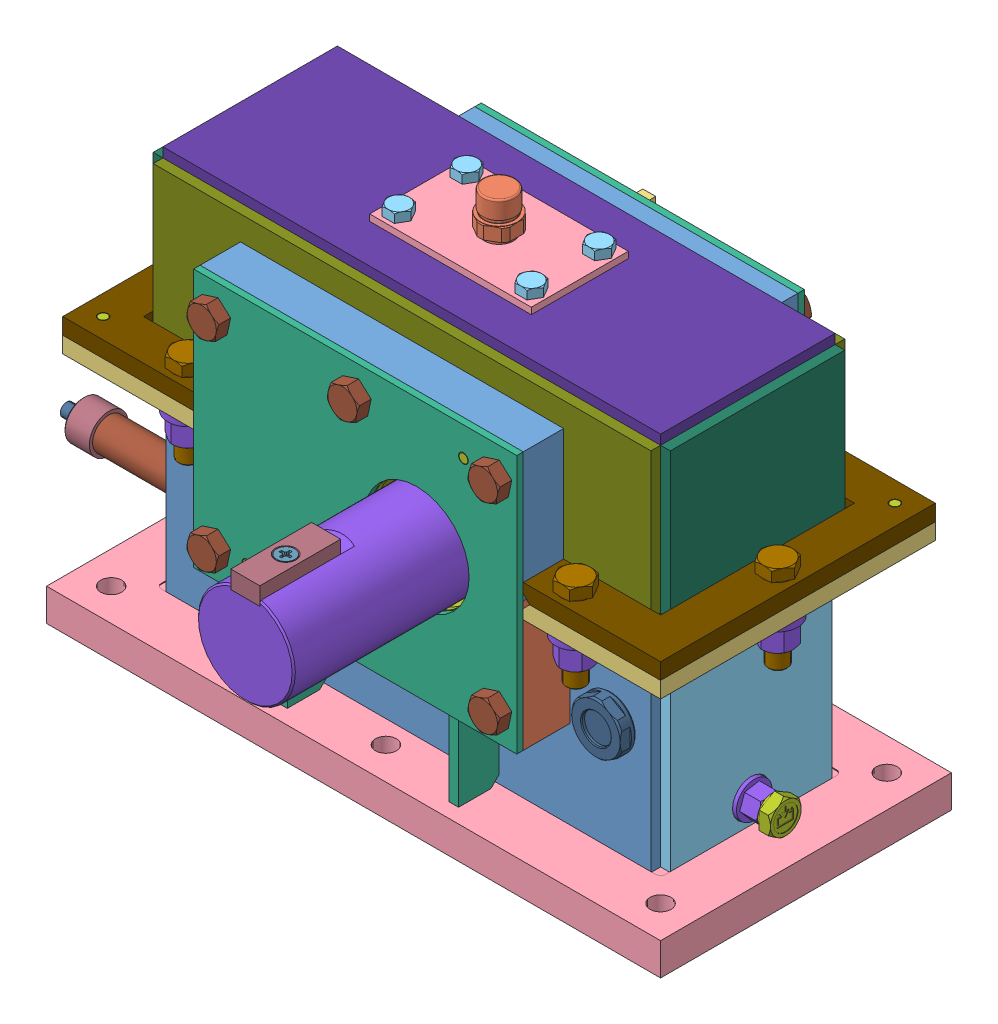
SolidWorks assembly reduktor, configuration Default. Lengths in mm.
Overall size (420 284 364.33).
123 component instances, 47 part files, 49 mates.
Components (placement in the parent):
- kuciste_bez_poklopca-1: kuciste_bez_poklopca [Default] at (-37.8332 -21.7055 -9.2797) size (410 284 180)
  - DONJE_KUCISTE-1: DONJE_KUCISTE [zajedno obrađeno] at (117.7992 130.0596 336.2434) size (410 154.5 180)
    - glavni_lim-1: glavni_lim [rupa za staklo] at (0 84.5 50) x (1 0 0) z (0 -1 0) size (300 6 130)
    - kockavratila-1: kockavratila [probusena_s_rupama_prednja] at (0 114.5 50) x (1 0 0) z (0 -1 0) size (200 35 80)
    - prirubnica_donja-1: prirubnica_donja [urezana_s_rupama] at (-100 144.5 0) size (85 10 170)
    - temeljna_ploca-1: temeljna_ploca [Default] at origin size (380 20 180)
    - bocni_lim-2: bocni_lim [cijevni registar] at (-150 84.5 0) x (0 0 -1) z (0 1 0) size (100 6 130)
    - glavni_lim-2: glavni_lim [Default] at (0 84.5 -56) x (1 0 0) z (0 -1 0) size (300 6 130)
    - kockavratila-2: kockavratila [probusena_s_rupama_zadnja] at (0 114.5 -50) x (-1 0 0) z (0 -1 0) size (200 35 80)
    - prirubnica_donja-2: prirubnica_donja [urezana_s_rupama] at (100 144.5 0) x (-1 0 0) z (0 0 -1) size (85 10 170)
    - bocni_lim-3: bocni_lim [irezan_ispust] at (156 84.5 0) x (0 0 1) z (0 -1 0) size (100 6 130)
    - rebro-1: rebro [Default] at (-50 47.25 68.5) x (0 -1 0) z (0 0 -1) size (54.5 6 25)
    - rebro-2: rebro [Default] at (50 47.25 68.5) x (0 1 0) z (0 0 -1) size (54.5 6 25)
    - rebro-3: rebro [Default] at (56 47.25 -68.5) x (0 1 0) z (0 0 1) size (54.5 6 25)
    - rebro-4: rebro [Default] at (-50 47.25 -68.5) x (0 1 0) z (0 0 1) size (54.5 6 25)
    - Oil fill plugs TCD.10x1.5-1: Oil fill plugs TCD.10x1.5 [Default] at (161.5 34.5 0) size (16 24.13 19)
    - Hexagon nut DIN 6331-M10-1: Hexagon nut DIN 6331-M10 [Default] at (154 34.5 0) x (0 -0.652064 0.758164) z (0 0.758164 0.652064) size (22 15 22)
    - Brass nut GH.M26x1.5-NK-1: Brass nut GH.M26x1.5-NK [Default] at (125 88.5 50) x (0 0 1) z (-0.706547 -0.707666 0) size (3.5 33 30)
    - Oil level sight glass GN 743-18-M26x1_5-A-1: Oil level sight glass GN 743-18-M26x1_5-A [Default] at (125 88.5 48) x (1 0 0) z (0 -1 0) size (32 17 32)
    - Prirubnica_c.reg._sklop-1: Prirubnica_c.reg._sklop [Default] at (-142.8722 78.3632 -24.5463) x (0 0.999301 0.037387) z (0 -0.037387 0.999301) size (33.22 66 33.22)
      - prirubnica_cijevnog_registra-1: prirubnica_cijevnog_registra [Default] at (-7.5365 11.1278 62.3717) size (20 50 20)
      - Gasket DIN 7603-AL-8-11_5-A(semering registra)-1: Gasket DIN 7603-AL-8-11_5-A(semering registra) [Default] at (-7.5365 26.6278 62.3717) x (0 -1 0) z (0.887885 0 0.460066) size (1 11.4 11.4)
      - Gasket DIN 7603-AL-8-11_5-A(semering registra)-2: Gasket DIN 7603-AL-8-11_5-A(semering registra) [Default] at (-7.5365 28.6278 62.3717) x (0 -1 0) z (-0.546944 0 0.837169) size (1 11.4 11.4)
      - Gasket DIN 7603-AL-8-11_5-A(semering registra)-3: Gasket DIN 7603-AL-8-11_5-A(semering registra) [Default] at (-7.5365 29.6278 62.3717) x (0 1 0) z (-0.564882 0 -0.825172) size (1 11.4 11.4)
      - Gasket DIN 7603-AL-8-11_5-A(semering registra)-4: Gasket DIN 7603-AL-8-11_5-A(semering registra) [Default] at (-7.5365 30.6278 62.3717) x (0 1 0) z (-0.564882 0 -0.825172) size (1 11.4 11.4)
      - Gasket DIN 7603-AL-8-11_5-A(semering registra)-5: Gasket DIN 7603-AL-8-11_5-A(semering registra) [Default] at (-7.5365 27.6278 62.3717) x (0 -1 0) z (-0.546944 0 0.837169) size (1 11.4 11.4)
      - M16x30-1: M16x30 [Default] at (-7.5365 77.1278 62.3717) x (0 -1 0) z (-0.546944 0 0.837169) size (46 24 24)
    - Prirubnica_c.reg._sklop-2: Prirubnica_c.reg._sklop [Default] at (-142.8722 84.718 -98.196) x (0 0.990097 0.140386) z (0 -0.140386 0.990097) size (33.22 66 33.22)
      - prirubnica_cijevnog_registra-1: prirubnica_cijevnog_registra [Default] at (-7.5365 11.1278 62.3717) size (20 50 20)
      - Gasket DIN 7603-AL-8-11_5-A(semering registra)-1: Gasket DIN 7603-AL-8-11_5-A(semering registra) [Default] at (-7.5365 26.6278 62.3717) x (0 -1 0) z (0.887885 0 0.460066) size (1 11.4 11.4)
      - Gasket DIN 7603-AL-8-11_5-A(semering registra)-2: Gasket DIN 7603-AL-8-11_5-A(semering registra) [Default] at (-7.5365 28.6278 62.3717) x (0 -1 0) z (-0.546944 0 0.837169) size (1 11.4 11.4)
      - Gasket DIN 7603-AL-8-11_5-A(semering registra)-3: Gasket DIN 7603-AL-8-11_5-A(semering registra) [Default] at (-7.5365 29.6278 62.3717) x (0 1 0) z (-0.564882 0 -0.825172) size (1 11.4 11.4)
      - Gasket DIN 7603-AL-8-11_5-A(semering registra)-4: Gasket DIN 7603-AL-8-11_5-A(semering registra) [Default] at (-7.5365 30.6278 62.3717) x (0 1 0) z (-0.564882 0 -0.825172) size (1 11.4 11.4)
      - Gasket DIN 7603-AL-8-11_5-A(semering registra)-5: Gasket DIN 7603-AL-8-11_5-A(semering registra) [Default] at (-7.5365 27.6278 62.3717) x (0 -1 0) z (-0.546944 0 0.837169) size (1 11.4 11.4)
      - M16x30-1: M16x30 [Default] at (-7.5365 77.1278 62.3717) x (0 -1 0) z (-0.546944 0 0.837169) size (46 24 24)
    - unutarnji lim-1: unutarnji lim [Default] at (-1.7035 28.2254 0) x (0.99863 -0.052336 0) z (0 0 -1) size (296.96 17.98 100)
  - GORNJE KUČIŠTE-1: GORNJE KUČIŠTE [zajednicki obrađena] at (84.6226 294.5596 336.2434) x (-1 0 0) z (0 0 1) size (370 129.5 170)
    - gornji bočni lim veći-1: gornji bočni lim veći [Default] at (-187.1766 -40 0) x (0 1 0) z (0 0 1) size (90 6 108)
    - gornji glavni lim-1: gornji glavni lim [Default] at (27.434 -40 -60) x (-1 0 0) z (0 1 0) size (308 6 90)
    - gornji_gornji lim ravni-1: gornji_gornji lim ravni [Default] at (-33.1766 -91 0) size (308 6 108)
    - prirubnica_gornja-1: prirubnica_gornja [prirubnica s rupama ] at origin size (85 10 170)
    - gornji bočni lim veći-2: gornji bočni lim veći [Default] at (126.8234 -40 0) x (0 1 0) z (0 0 1) size (90 6 108)
    - gornji glavni lim-2: gornji glavni lim [Default] at (-93.7872 -40 60) x (1 0 0) z (0 1 0) size (308 6 90)
    - prirubnica_gornja-2: prirubnica_gornja [prirubnica s rupama ] at (-66.3532 0 0) x (-1 0 0) z (0 0 -1) size (85 10 170)
    - gornja kocka vratila-1: gornja kocka vratila [prednja_probusena_s_rupama] at (-33.1766 -30 50) x (-1 0 0) z (0 1 0) size (200 35 80)
    - gornja kocka vratila-2: gornja kocka vratila [zadnja_probusena_s_rupama] at (-33.1766 -30 -50) x (1 0 0) z (0 1 0) size (200 35 80)
    - poklopac sa odzračnikom-1: poklopac sa odzračnikom [Default] at (-34.3484 -81.4985 -29.5408) x (-1 0 0) z (0 0 1) size (100 33 60)
      - Breather valve GN 881-M12x1_5-200-MS-M-1: Breather valve GN 881-M12x1_5-200-MS-M [Default] at (-1.1718 13.5015 29.5408) size (23 33 23.5)
      - Mounting nut GN 7430-M12x1_5-MS-1: Mounting nut GN 7430-M12x1_5-MS [Default] at (-1.1718 6.5015 29.5408) x (1 0 0) z (0 -1 0) size (16 17.5 3)
      - poklopac-1: poklopac [Default] at (-1.1718 9.5015 29.5408) size (100 4 60)
    - DIN933 M8x14mm-1: DIN933 M8x14mm [Default] at (-74.1766 -100.68 21) x (0 1 0) z (0 0 1) size (19.69 15.02 15.02)
    - DIN933 M8x14mm-2: DIN933 M8x14mm [Default] at (7.8234 -100.68 21) x (0 1 0) z (0 0 1) size (19.69 15.02 15.02)
    - DIN933 M8x14mm-3: DIN933 M8x14mm [Default] at (7.8234 -100.68 -21) x (0 1 0) z (0 0 1) size (19.69 15.02 15.02)
    - DIN933 M8x14mm-4: DIN933 M8x14mm [Default] at (-74.1766 -100.68 -21) x (0 1 0) z (0 0 1) size (19.69 15.02 15.02)
  - poklopac_vratila-1: poklopac_vratila [zajedno_obrađen_prednji] at (117.7992 284.5596 425.2434) x (1 0 0) z (0 1 0) size (200 17.13 160)
  - poklopac_vratila-2: poklopac_vratila [zajedno_obrađen] at (117.7992 284.5596 247.2434) x (1 0 0) z (0 -1 0) size (200 17.13 160)
  - parallel pin hardened_din-1: parallel pin hardened_din [DIN EN 28734 - 6 x 14 - A - St] at (290.2992 280.5596 263.7434) x (0 1 0) z (0 0 1) size (14 6 6)
  - parallel pin hardened_din-2: parallel pin hardened_din [DIN EN 28734 - 6 x 14 - A - St] at (184.7992 346.5596 411.2434) x (0 0 1) z (0 -1 0) size (14 6 6)
  - parallel pin hardened_din-3: parallel pin hardened_din [DIN EN 28734 - 6 x 14 - A - St] at (50.7992 222.5596 411.2434) x (0 0 1) z (-1 0 0) size (14 6 6)
  - parallel pin hardened_din-4: parallel pin hardened_din [DIN EN 28734 - 6 x 14 - A - St] at (50.7992 222.5596 247.2434) x (0 0 1) z (-1 0 0) size (14 6 6)
  - parallel pin hardened_din-5: parallel pin hardened_din [DIN EN 28734 - 6 x 14 - A - St] at (-54.7008 280.5596 408.7434) x (0 1 0) z (0 0 1) size (14 6 6)
  - parallel pin hardened_din-6: parallel pin hardened_din [DIN EN 28734 - 6 x 14 - A - St] at (184.7992 346.5596 247.2434) x (0 0 1) z (-1 0 0) size (14 6 6)
- podsklop_v2-1: podsklop_v2 [Default] at (87.5598 229.7035 557.949) x (0 0 1) z (0 1 0) size (286.33 152 152)
  - vratilo_2-1: vratilo_2 [Default] at (-307.9854 30.4063 33.1505) x (1 0 0) z (0 -1 0) size (272 65 65)
  - zupcanik_2-1: zupcanik_2 [Default] at (-193.4854 30.4063 33.1505) x (0 -1 0) z (-1 0 0) size (152 152 75)
  - skf_bearing_nup_212_ecm_2-1: skf_bearing_nup_212_ecm_2 [Default] at (-180.9854 30.4063 33.1505) size (22 110 110)
    - skf_bearing_nup_212_ecm_2_01-1: skf_bearing_nup_212_ecm_2_01 [Default] at origin size (22 77.5 77.5)
    - skf_bearing_nup_212_ecm_2_02-1: skf_bearing_nup_212_ecm_2_02 [Default] at origin size (22 110 110)
    - skf_bearing_nup_212_ecm_2_03-1: skf_bearing_nup_212_ecm_2_03 [Default] at origin size (14 100 100)
  - skf_bearing_nup_212_ecm_2-2: skf_bearing_nup_212_ecm_2 [Default] at (-302.9854 30.4063 33.1505) size (22 110 110)
    - skf_bearing_nup_212_ecm_2_01-1: skf_bearing_nup_212_ecm_2_01 [Default] at origin size (22 77.5 77.5)
    - skf_bearing_nup_212_ecm_2_02-1: skf_bearing_nup_212_ecm_2_02 [Default] at origin size (22 110 110)
    - skf_bearing_nup_212_ecm_2_03-1: skf_bearing_nup_212_ecm_2_03 [Default] at origin size (14 100 100)
  - pero_zupcanika-1: pero_zupcanika [Default] at (-255.9854 30.4063 58.8505) x (1 0 0) z (0 -1 0) size (68 11 18)
  - pero_zupcanika-2: pero_zupcanika [za_spojku2] at (-85.9854 30.4063 58.8505) x (1 0 0) z (0 -1 0) size (75.25 11 18)
  - countersunk flat head cross recess screw_din-2: countersunk flat head cross recess screw_din [DIN EN ISO 7046-1 - M6 x 12 - Z - 12N] at (-60.9854 30.4063 69.8505) x (0 0 -1) z (0.999719 0.023723 0) size (12 11.3 11.3)
  - circlip for shafts normal_din-2: circlip for shafts normal_din [Circlip DIN 471 - 60 x 2] at (-305.1354 30.4063 33.1505) x (0 0 1) z (-1 0 0) size (65.65 70.2 2)
  - distantni_prsten-1: distantni_prsten [Default] at (-180.9854 30.4063 33.1505) x (0 1 0) z (0 0 1) size (70 12.5 70)
  - distantni_prsten-2: distantni_prsten [Default] at (-268.4854 30.4063 33.1505) x (0 1 0) z (0 0 1) size (70 12.5 70)
- podsklop_v1-1: podsklop_v1 [Default] at (-174.373 416.0168 275.401) x (0 0 1) z (1 0 0) size (230 81.89 81.89)
  - Vratilo_1-1: Vratilo_1 [Default] at (-103.4374 153.1627 192.3391) size (230 63.09 60.45)
  - skf_bearing_nup_2206_ecp_2-1: skf_bearing_nup_2206_ecp_2 [Default] at (-18.4374 153.1627 192.3391) size (20 62 62)
    - skf_bearing_nup_2206_ecp_2_01-1: skf_bearing_nup_2206_ecp_2_01 [Default] at origin size (20 41.2 41.2)
    - skf_bearing_nup_2206_ecp_2_02-1: skf_bearing_nup_2206_ecp_2_02 [Default] at origin size (20 62 62)
    - skf_bearing_nup_2206_ecp_2_03-1: skf_bearing_nup_2206_ecp_2_03 [Default] at origin size (13 54.82 55.16)
  - skf_bearing_nup_2206_ecp_2-2: skf_bearing_nup_2206_ecp_2 [Default] at (101.5626 153.1627 192.3391) x (1 0 0) z (0 -0.407591 0.913164) size (20 62 62)
    - skf_bearing_nup_2206_ecp_2_01-1: skf_bearing_nup_2206_ecp_2_01 [Default] at origin size (20 41.2 41.2)
    - skf_bearing_nup_2206_ecp_2_02-1: skf_bearing_nup_2206_ecp_2_02 [Default] at origin size (20 62 62)
    - skf_bearing_nup_2206_ecp_2_03-1: skf_bearing_nup_2206_ecp_2_03 [Default] at origin size (13 54.82 55.16)
  - pero-1: pero [Default] at (-73.4374 142.2627 192.3391) x (-1 0 0) z (0 -1 0) size (60 8 7)
  - circlip for shafts normal_din-3: circlip for shafts normal_din [Circlip DIN 471 - 30 x 1.5] at (121.5626 153.1627 192.3391) x (0 0 1) z (-1 0 0) size (33.78 37.1 1.5)
  - countersunk flat head cross recess screw_din-4: countersunk flat head cross recess screw_din [DIN EN ISO 7046-1 - M3 x 10 - Z - 10N] at (-73.4374 135.2627 192.3391) x (0 1 0) z (-0.99395 0 0.109831) size (10 5.5 5.5)
- o-ring_fi110-1: o-ring_fi110 [Default] at (117.9661 262.8541 243.2636) x (-0.826987 0.562221 0) z (0.562221 0.826987 0) size (115.2 2.6 115.2)
- o-ring_fi62-1: o-ring_fi62 [fi62] at (17.9661 262.8541 243.2636) x (1 0 0) z (0 1 0) size (67.2 2.6 67.2)
- o-ring_fi110-2: o-ring_fi110 [Default] at (117.9661 262.8541 410.6636) x (1 0 0) z (0 -1 0) size (115.2 2.6 115.2)
- o-ring_fi62-2: o-ring_fi62 [fi62] at (17.9661 262.8541 410.6636) x (1 0 0) z (0 -1 0) size (67.2 2.6 67.2)
- semeringfi30-1: semeringfi30 [Default] at (17.9661 262.8541 241.9636) x (0 0 1) z (-0.999998 0.002207 0) size (10 52 52)
- semeringfi60-1: semeringfi60 [Default] at (117.9661 262.8541 411.9636) x (0 0 -1) z (1 0 0) size (10 85 85)
- hex collar nut 1.5d height_din-2: hex collar nut 1.5d height_din [DIN 6331-M12-N] at (-40.0339 234.8541 399.4636) x (1 0 0) z (0 -1 0) size (25 25 18)
- hex collar nut 1.5d height_din-3: hex collar nut 1.5d height_din [DIN 6331-M12-N] at (-92.5339 234.8541 326.9636) x (1 0 0) z (0 -1 0) size (25 25 18)
- hex collar nut 1.5d height_din-4: hex collar nut 1.5d height_din [DIN 6331-M12-N] at (-40.0339 234.8541 254.4636) x (1 0 0) z (0 -1 0) size (25 25 18)
- hex collar nut 1.5d height_din-5: hex collar nut 1.5d height_din [DIN 6331-M12-N] at (199.9661 234.8541 254.4636) x (1 0 0) z (0 -1 0) size (25 25 18)
- hex collar nut 1.5d height_din-6: hex collar nut 1.5d height_din [DIN 6331-M12-N] at (252.466 234.8541 326.9636) x (1 0 0) z (0 -1 0) size (25 25 18)
- hex collar nut 1.5d height_din-8: hex collar nut 1.5d height_din [DIN 6331-M12-N] at (199.9661 234.8541 399.4636) x (1 0 0) z (0 -1 0) size (25 25 18)
- hex bolt gradeab_din-2: hex bolt gradeab_din [DIN EN 24014 - M12 x 50 x 30-N] at (-92.5339 280.3541 326.9636) x (0 -1 0) z (0 0 1) size (57.5 20.78 18)
- hex bolt gradeab_din-3: hex bolt gradeab_din [DIN EN 24014 - M12 x 50 x 30-N] at (-40.0339 280.3541 399.4636) x (0 -1 0) z (0 0 1) size (57.5 20.78 18)
- hex bolt gradeab_din-4: hex bolt gradeab_din [DIN EN 24014 - M12 x 50 x 30-N] at (-40.0339 280.3541 254.4636) x (0 -1 0) z (0 0 1) size (57.5 20.78 18)
- hex bolt gradeab_din-5: hex bolt gradeab_din [DIN EN 24014 - M12 x 50 x 30-N] at (199.9661 280.3541 254.4636) x (0 -1 0) z (0 0 1) size (57.5 20.78 18)
- hex bolt gradeab_din-6: hex bolt gradeab_din [DIN EN 24014 - M12 x 50 x 30-N] at (252.466 280.3541 326.9636) x (0 -1 0) z (0 0 1) size (57.5 20.78 18)
- hex bolt gradeab_din-7: hex bolt gradeab_din [DIN EN 24014 - M12 x 50 x 30-N] at (199.9661 280.3541 399.4636) x (0 -1 0) z (0 0 1) size (57.5 20.78 18)
- cijevni_reg-1: cijevni_reg [Default] at (-70.0339 176.8541 289.4636) size (316.5 33.17 83)
- DIN933 M12x20mm-1: DIN933 M12x20mm [Default] at (166.9661 324.8541 230.0136) x (0 0 1) z (-0.923728 -0.383049 0) size (27.95 20.79 20.79)
- DIN933 M12x20mm-2: DIN933 M12x20mm [Default] at (79.9661 324.8541 230.0136) x (0 0 1) z (-0.923728 -0.383049 0) size (27.95 20.79 20.79)
- DIN933 M12x20mm-3: DIN933 M12x20mm [Default] at (-7.0339 324.8541 230.0136) x (0 0 1) z (-0.923728 -0.383049 0) size (27.95 20.79 20.79)
- DIN933 M12x20mm-4: DIN933 M12x20mm [Default] at (166.9661 200.8541 230.0136) x (0 0 1) z (-0.923728 -0.383049 0) size (27.95 20.79 20.79)
- DIN933 M12x20mm-6: DIN933 M12x20mm [Default] at (79.9661 200.8541 230.0136) x (0 0 1) z (-0.923728 -0.383049 0) size (27.95 20.79 20.79)
- DIN933 M12x20mm-8: DIN933 M12x20mm [Default] at (-7.0339 200.8541 230.0136) x (0 0 1) z (-0.923728 -0.383049 0) size (27.95 20.79 20.79)
- DIN933 M12x20mm-10: DIN933 M12x20mm [Default] at (-7.0339 324.8541 423.9136) x (0 0 -1) z (0.669151 0.743126 0) size (27.95 20.79 20.79)
- DIN933 M12x20mm-11: DIN933 M12x20mm [Default] at (79.9661 324.8541 423.9136) x (0 0 -1) z (0.669151 0.743126 0) size (27.95 20.79 20.79)
- DIN933 M12x20mm-12: DIN933 M12x20mm [Default] at (166.9661 324.8541 423.9136) x (0 0 -1) z (0.669151 0.743126 0) size (27.95 20.79 20.79)
- DIN933 M12x20mm-13: DIN933 M12x20mm [Default] at (-7.0339 200.8541 423.9136) x (0 0 -1) z (0.669151 0.743126 0) size (27.95 20.79 20.79)
- DIN933 M12x20mm-14: DIN933 M12x20mm [Default] at (79.9661 200.8541 423.9136) x (0 0 -1) z (0.669151 0.743126 0) size (27.95 20.79 20.79)
- DIN933 M12x20mm-15: DIN933 M12x20mm [Default] at (166.9661 200.8541 423.9136) x (0 0 -1) z (0.669151 0.743126 0) size (27.95 20.79 20.79)
Mates (geometry in assembly coordinates):
- Concentric1: concentric anti-aligned: cylinder of kuciste_bez_poklopca-1/DONJE_KUCISTE-1/kockavratila-1 through (117.9661 262.8541 221.4001) axis (0 0 1) radius 55; cylinder of podsklop_v2-1/vratilo_2-1 through (117.9661 262.8541 249.9636) axis (0 0 -1) radius 30
- Coincident1: coincident aligned: plane of kuciste_bez_poklopca-1/DONJE_KUCISTE-1/kockavratila-1 through (79.9661 222.8541 376.9636) normal (0 0 -1); plane of podsklop_v2-1/skf_bearing_nup_212_ecm_2-1/skf_bearing_nup_212_ecm_2_02-1 through (168.6411 262.8541 376.9636) normal (0 0 -1)
- Parallel1: parallel aligned: plane of kuciste_bez_poklopca-1/GORNJE KUČIŠTE-1/gornja kocka vratila-1 through (-20.0339 342.8541 411.9636) normal (0 1 0); plane of podsklop_v2-1/pero_zupcanika-2 through (117.9661 299.5541 471.9636) normal (0 1 0)
- Concentric2: concentric aligned: cylinder of kuciste_bez_poklopca-1/DONJE_KUCISTE-1/kockavratila-1 through (17.9661 262.8541 221.4001) axis (0 0 1) radius 31; cylinder of podsklop_v1-1/Vratilo_1-1 through (17.9661 262.8541 401.9636) axis (0 0 1) radius 15
- Coincident3: coincident aligned: plane of kuciste_bez_poklopca-1/DONJE_KUCISTE-1/kockavratila-2 through (79.9661 222.8541 276.9636) normal (0 0 1); plane of podsklop_v1-1/skf_bearing_nup_2206_ecp_2-1/skf_bearing_nup_2206_ecp_2_02-1 through (17.9661 234.7666 276.9636) normal (0 0 1)
- Parallel2: parallel aligned: plane of kuciste_bez_poklopca-1/GORNJE KUČIŠTE-1/gornja kocka vratila-2 through (179.9661 342.8541 241.9636) normal (0 1 0); plane of podsklop_v1-1/pero-1 through (17.9661 280.7541 201.9636) normal (0 1 0)
- Concentric3: concentric aligned: circle of kuciste_bez_poklopca-1/poklopac_vratila-2; circle of o-ring_fi110-1
- Tangent6: tangent anti-aligned: plane of kuciste_bez_poklopca-1/poklopac_vratila-2 through (79.9661 262.8541 241.9636) normal (0 0 1); torus of o-ring_fi110-1
- Concentric4: concentric anti-aligned: circle of kuciste_bez_poklopca-1/poklopac_vratila-2; circle of o-ring_fi62-1
- Tangent9: tangent anti-aligned: plane of kuciste_bez_poklopca-1/poklopac_vratila-2 through (79.9661 262.8541 241.9636) normal (0 0 1); torus of o-ring_fi62-1
- Concentric5: concentric anti-aligned: cylinder of podsklop_v1-1/skf_bearing_nup_2206_ecp_2-2/skf_bearing_nup_2206_ecp_2_02-1 through (17.9661 262.8541 386.9636) axis (0 0 -1) radius 31; circle of o-ring_fi62-2
- Tangent10: tangent anti-aligned: plane of kuciste_bez_poklopca-1/poklopac_vratila-1 through (79.9661 262.8541 411.9636) normal (0 0 -1); torus of o-ring_fi62-2
- Concentric6: concentric anti-aligned: cylinder of podsklop_v2-1/skf_bearing_nup_212_ecm_2-1/skf_bearing_nup_212_ecm_2_02-1 through (117.9661 262.8541 387.9636) axis (0 0 -1) radius 55; circle of o-ring_fi110-2
- Tangent11: tangent anti-aligned: plane of kuciste_bez_poklopca-1/poklopac_vratila-1 through (79.9661 262.8541 411.9636) normal (0 0 -1); torus of o-ring_fi110-2
- Concentric9: concentric anti-aligned: cylinder of kuciste_bez_poklopca-1/poklopac_vratila-1 through (117.9661 262.8541 398.9636) axis (0 0 1) radius 42.5; cylinder of semeringfi60-1 through (117.9661 262.8541 401.9636) axis (0 0 -1) radius 42.5
- Coincident6: coincident anti-aligned: plane of kuciste_bez_poklopca-1/poklopac_vratila-1 through (79.9661 262.8541 411.9636) normal (0 0 -1); plane of semeringfi60-1 through (75.4661 219.8831 411.9636) normal (0 0 1)
- Concentric10: concentric anti-aligned: cylinder of kuciste_bez_poklopca-1/poklopac_vratila-2 through (17.9661 262.8541 254.9636) axis (0 0 -1) radius 26; cylinder of semeringfi30-1 through (17.9661 262.8541 251.9636) axis (0 0 1) radius 26
- Coincident7: coincident anti-aligned: plane of kuciste_bez_poklopca-1/poklopac_vratila-2 through (79.9661 262.8541 241.9636) normal (0 0 1); plane of semeringfi30-1 through (43.9075 236.3138 241.9636) normal (0 0 -1)
- Concentric11: concentric anti-aligned: cylinder of kuciste_bez_poklopca-1/DONJE_KUCISTE-1/prirubnica_donja-1 through (-40.0339 252.8541 399.4636) axis (0 1 0) radius 6.5; cylinder of hex collar nut 1.5d height_din-2 through (-40.0339 259.8916 399.4636) axis (0 -1 0) radius 6
- Coincident8: coincident anti-aligned: plane of kuciste_bez_poklopca-1/DONJE_KUCISTE-1/prirubnica_donja-1 through (-20.0339 252.8541 326.9636) normal (0 -1 0); plane of hex collar nut 1.5d height_din-2 through (-40.0339 252.8541 409.8559) normal (0 1 0)
- Concentric12: concentric anti-aligned: cylinder of kuciste_bez_poklopca-1/DONJE_KUCISTE-1/prirubnica_donja-1 through (-92.5339 252.8541 326.9636) axis (0 1 0) radius 6.5; cylinder of hex collar nut 1.5d height_din-3 through (-92.5339 259.8916 326.9636) axis (0 -1 0) radius 6
- Coincident9: coincident anti-aligned: plane of kuciste_bez_poklopca-1/DONJE_KUCISTE-1/prirubnica_donja-1 through (-20.0339 252.8541 326.9636) normal (0 -1 0); plane of hex collar nut 1.5d height_din-3 through (-92.5339 252.8541 337.3559) normal (0 1 0)
- Concentric13: concentric anti-aligned: cylinder of kuciste_bez_poklopca-1/DONJE_KUCISTE-1/prirubnica_donja-1 through (-40.0339 252.8541 254.4636) axis (0 1 0) radius 6.5; cylinder of hex collar nut 1.5d height_din-4 through (-40.0339 259.8916 254.4636) axis (0 -1 0) radius 6
- Coincident10: coincident anti-aligned: plane of kuciste_bez_poklopca-1/DONJE_KUCISTE-1/prirubnica_donja-1 through (-20.0339 252.8541 326.9636) normal (0 -1 0); plane of hex collar nut 1.5d height_din-4 through (-40.0339 252.8541 264.8559) normal (0 1 0)
- Concentric14: concentric anti-aligned: cylinder of kuciste_bez_poklopca-1/DONJE_KUCISTE-1/prirubnica_donja-2 through (199.9661 252.8541 254.4636) axis (0 1 0) radius 6.5; cylinder of hex collar nut 1.5d height_din-5 through (199.9661 259.8916 254.4636) axis (0 -1 0) radius 6
- Coincident11: coincident anti-aligned: plane of kuciste_bez_poklopca-1/DONJE_KUCISTE-1/prirubnica_donja-2 through (179.9661 252.8541 326.9636) normal (0 -1 0); plane of hex collar nut 1.5d height_din-5 through (199.9661 252.8541 264.8559) normal (0 1 0)
- Concentric15: concentric anti-aligned: cylinder of kuciste_bez_poklopca-1/DONJE_KUCISTE-1/prirubnica_donja-2 through (252.466 252.8541 326.9636) axis (0 1 0) radius 6.5; cylinder of hex collar nut 1.5d height_din-6 through (252.466 259.8916 326.9636) axis (0 -1 0) radius 6
- Coincident12: coincident anti-aligned: plane of kuciste_bez_poklopca-1/DONJE_KUCISTE-1/prirubnica_donja-2 through (179.9661 252.8541 326.9636) normal (0 -1 0); plane of hex collar nut 1.5d height_din-6 through (252.466 252.8541 337.3559) normal (0 1 0)
- Concentric17: concentric anti-aligned: cylinder of kuciste_bez_poklopca-1/DONJE_KUCISTE-1/prirubnica_donja-2 through (199.9661 252.8541 399.4636) axis (0 1 0) radius 6.5; cylinder of hex collar nut 1.5d height_din-8 through (199.9661 259.8916 399.4636) axis (0 -1 0) radius 6
- Coincident13: coincident anti-aligned: plane of kuciste_bez_poklopca-1/DONJE_KUCISTE-1/prirubnica_donja-2 through (179.9661 252.8541 326.9636) normal (0 -1 0); plane of hex collar nut 1.5d height_din-8 through (199.9661 252.8541 409.8559) normal (0 1 0)
- Concentric18: concentric aligned: cylinder of kuciste_bez_poklopca-1/GORNJE KUČIŠTE-1/prirubnica_gornja-2 through (-92.5339 262.8541 326.9636) axis (0 1 0) radius 6.5; cylinder of hex bolt gradeab_din-2 through (-92.5339 280.3541 326.9636) axis (0 1 0) radius 9
- Coincident14: coincident anti-aligned: plane of kuciste_bez_poklopca-1/GORNJE KUČIŠTE-1/prirubnica_gornja-2 through (113.1427 272.8541 326.9636) normal (0 1 0); plane of hex bolt gradeab_din-2 through (-92.5339 272.8541 308.9636) normal (0 -1 0)
- Concentric19: concentric aligned: cylinder of kuciste_bez_poklopca-1/GORNJE KUČIŠTE-1/prirubnica_gornja-2 through (-40.0339 262.8541 399.4636) axis (0 1 0) radius 6.5; cylinder of hex bolt gradeab_din-3 through (-40.0339 280.3541 399.4636) axis (0 1 0) radius 9
- Coincident15: coincident anti-aligned: plane of kuciste_bez_poklopca-1/GORNJE KUČIŠTE-1/prirubnica_gornja-2 through (113.1427 272.8541 326.9636) normal (0 1 0); plane of hex bolt gradeab_din-3 through (-40.0339 272.8541 381.4636) normal (0 -1 0)
- Concentric20: concentric aligned: cylinder of kuciste_bez_poklopca-1/GORNJE KUČIŠTE-1/prirubnica_gornja-2 through (-40.0339 262.8541 254.4636) axis (0 1 0) radius 6.5; cylinder of hex bolt gradeab_din-4 through (-40.0339 280.3541 254.4636) axis (0 1 0) radius 9
- Coincident16: coincident anti-aligned: plane of kuciste_bez_poklopca-1/GORNJE KUČIŠTE-1/prirubnica_gornja-2 through (113.1427 272.8541 326.9636) normal (0 1 0); plane of hex bolt gradeab_din-4 through (-40.0339 272.8541 236.4636) normal (0 -1 0)
- Concentric21: concentric aligned: cylinder of kuciste_bez_poklopca-1/GORNJE KUČIŠTE-1/prirubnica_gornja-1 through (199.9661 262.8541 254.4636) axis (0 1 0) radius 6.5; cylinder of hex bolt gradeab_din-5 through (199.9661 280.3541 254.4636) axis (0 1 0) radius 9
- Coincident17: coincident anti-aligned: plane of kuciste_bez_poklopca-1/GORNJE KUČIŠTE-1/prirubnica_gornja-1 through (46.7895 272.8541 326.9636) normal (0 1 0); plane of hex bolt gradeab_din-5 through (199.9661 272.8541 236.4636) normal (0 -1 0)
- Concentric22: concentric aligned: cylinder of kuciste_bez_poklopca-1/GORNJE KUČIŠTE-1/prirubnica_gornja-1 through (252.466 262.8541 326.9636) axis (0 1 0) radius 6.5; cylinder of hex bolt gradeab_din-6 through (252.466 280.3541 326.9636) axis (0 1 0) radius 9
- Coincident18: coincident anti-aligned: plane of kuciste_bez_poklopca-1/GORNJE KUČIŠTE-1/prirubnica_gornja-1 through (46.7895 272.8541 326.9636) normal (0 1 0); plane of hex bolt gradeab_din-6 through (252.466 272.8541 308.9636) normal (0 -1 0)
- Concentric23: concentric aligned: cylinder of kuciste_bez_poklopca-1/GORNJE KUČIŠTE-1/prirubnica_gornja-1 through (199.9661 262.8541 399.4636) axis (0 1 0) radius 6.5; cylinder of hex bolt gradeab_din-7 through (199.9661 280.3541 399.4636) axis (0 1 0) radius 9
- Coincident19: coincident anti-aligned: plane of kuciste_bez_poklopca-1/GORNJE KUČIŠTE-1/prirubnica_gornja-1 through (46.7895 272.8541 326.9636) normal (0 1 0); plane of hex bolt gradeab_din-7 through (199.9661 272.8541 381.4636) normal (0 -1 0)
- Coincident20: coincident aligned: circle of kuciste_bez_poklopca-1/DONJE_KUCISTE-1/bocni_lim-2; cylinder of cijevni_reg-1 through (-70.0339 176.8541 289.4636) axis (-1 0 0) radius 4
- Concentric24: concentric anti-aligned: cylinder of kuciste_bez_poklopca-1/DONJE_KUCISTE-1/Prirubnica_c.reg._sklop-1/M16x30-1 through (-94.0339 176.8541 364.4636) axis (-1 0 0) radius 4; cylinder of cijevni_reg-1 through (-150.0339 176.8541 364.4628) axis (1 0 0) radius 3
- Distance1: distance = 10 mm aligned: plane of cijevni_reg-1 through (-150.0339 176.8541 364.4628) normal (-1 0 0); plane of kuciste_bez_poklopca-1/DONJE_KUCISTE-1/Prirubnica_c.reg._sklop-1/M16x30-1 through (-140.0339 176.8541 364.4636) normal (-1 0 0)
- Concentric25: concentric aligned: circle of kuciste_bez_poklopca-1/poklopac_vratila-2; circle of DIN933 M12x20mm-1
- Coincident21: coincident anti-aligned: plane of kuciste_bez_poklopca-1/poklopac_vratila-2 through (79.9661 262.8541 237.9636) normal (0 0 -1); plane of DIN933 M12x20mm-1 through (162.9853 334.4537 237.9636) normal (0 0 1)
- Concentric26: concentric aligned: circle of kuciste_bez_poklopca-1/poklopac_vratila-1; circle of DIN933 M12x20mm-10
- Coincident22: coincident anti-aligned: plane of kuciste_bez_poklopca-1/poklopac_vratila-1 through (79.9661 262.8541 415.9636) normal (0 0 1); plane of DIN933 M12x20mm-10 through (-14.7567 331.8081 415.9636) normal (0 0 -1)
